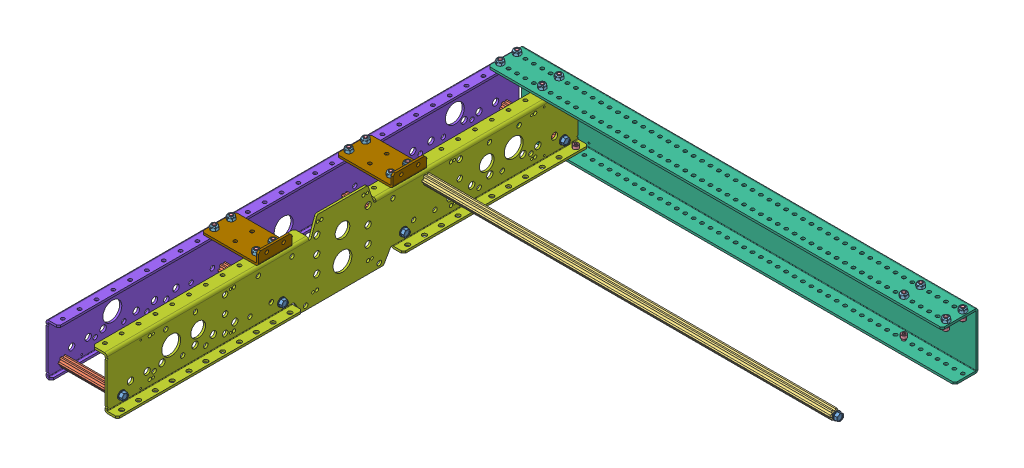
SolidWorks assembly AM14U3 Square Frame Half, configuration Default. Lengths in mm.
Overall size (722.38 116.33 715.14).
56 component instances, 9 part files, 120 mates.
Components (placement in the parent):
- 0.25-20 x 0.75 in Thread Rolling Screw-1: 0.25-20 x 0.75 in Thread Rolling Screw [FHTS 0.25-20-G-0.75-C] at (-600.075 -67.691 639.064) x (-1 0 0) z (0 0.924225 0.381849) size (24.64 12.19 12.19)
- 0.25-20 x 0.75 in Thread Rolling Screw-4: 0.25-20 x 0.75 in Thread Rolling Screw [FHTS 0.25-20-G-0.75-C] at (-600.075 -67.691 -27.94) x (-1 0 0) z (0 0.924225 0.381849) size (24.64 12.19 12.19)
- 0.25-20 x 0.75 in Thread Rolling Screw-5: 0.25-20 x 0.75 in Thread Rolling Screw [FHTS 0.25-20-G-0.75-C] at (-692.15 -67.691 -27.813) size (24.64 12.19 12.19)
- 0.25-20 x 0.75 in Thread Rolling Screw-7: 0.25-20 x 0.75 in Thread Rolling Screw [FHTS 0.25-20-G-0.75-C] at (-603.25 -15.494 178.562) size (24.64 12.19 12.19)
- 0.25-20 x 0.75 in Thread Rolling Screw-9: 0.25-20 x 0.75 in Thread Rolling Screw [FHTS 0.25-20-G-0.75-C] at (-692.15 -67.691 638.937) size (24.64 12.19 12.19)
- 0.25-20 x 0.75 in Thread Rolling Screw-10: 0.25-20 x 0.75 in Thread Rolling Screw [FHTS 0.25-20-G-0.75-C] at (19.05 -15.494 178.562) x (-1 0 0) z (0 0.525103 -0.851039) size (24.64 12.19 12.19)
- 500 Churro 3.375 in-1: 500 Churro 3.375 in [Default] at (-603.25 -67.691 -27.813) x (0 -0.866025 0.5) z (-1 0 0) size (14.66 12.7 85.72)
- 500 Churro 3.375 in-2: 500 Churro 3.375 in [Default] at (-603.25 -67.691 638.937) x (0 -0.866025 0.5) z (-1 0 0) size (14.66 12.7 85.72)
- 500 Churro 24.25 in-1: 500 Churro 24.25 in [Default] at (15.875 -15.494 178.562) x (0 0 -1) z (-1 0 0) size (14.66 12.7 615.95)
- 10-32 x 0.5 in SHCS Screw-19: 10-32 x 0.5 in SHCS Screw [HX-SHCS 0.19-32x1.375x1-C] at (-679.45 -11.43 -11.938) x (0 1 0) z (0 0 1) size (17.53 7.94 7.94)
- 10-32 x 0.5 in SHCS Screw-20: 10-32 x 0.5 in SHCS Screw [HX-SHCS 0.19-32x1.375x1-C] at (-679.45 -11.43 -37.338) x (0 1 0) z (0 0 1) size (17.53 7.94 7.94)
- 10-32 x 0.5 in SHCS Screw-21: 10-32 x 0.5 in SHCS Screw [HX-SHCS 0.19-32x1.375x1-C] at (-615.95 -11.43 -37.338) x (0 1 0) z (0 0 1) size (17.53 7.94 7.94)
- 10-32 x 0.5 in SHCS Screw-22: 10-32 x 0.5 in SHCS Screw [HX-SHCS 0.19-32x1.375x1-C] at (-615.95 -11.43 -11.938) x (0 1 0) z (0 0 1) size (17.53 7.94 7.94)
- 10-32 x 0.5 in SHCS Screw-23: 10-32 x 0.5 in SHCS Screw [HX-SHCS 0.19-32x1.375x1-C] at (-590.55 -73.152 -37.338) x (0 -1 0) z (0 0 1) size (17.53 7.94 7.94)
- 10-32 x 0.5 in SHCS Screw-24: 10-32 x 0.5 in SHCS Screw [HX-SHCS 0.19-32x1.375x1-C] at (-6.35 -11.176 -37.338) x (0 1 0) z (0.222581 0 0.974914) size (17.53 7.94 7.94)
- 10-32 x 0.5 in SHCS Screw-25: 10-32 x 0.5 in SHCS Screw [HX-SHCS 0.19-32x1.375x1-C] at (-6.35 -11.176 -11.938) x (0 1 0) z (0.81526 0 0.579096) size (17.53 7.94 7.94)
- 10-32 x 0.5 in SHCS Screw-26: 10-32 x 0.5 in SHCS Screw [HX-SHCS 0.19-32x1.375x1-C] at (-69.85 -11.176 -37.338) x (0 1 0) z (0 0 1) size (17.53 7.94 7.94)
- 10-32 x 0.5 in SHCS Screw-27: 10-32 x 0.5 in SHCS Screw [HX-SHCS 0.19-32x1.375x1-C] at (-69.85 -11.176 -11.938) x (0 1 0) z (0.111454 0 0.99377) size (17.53 7.94 7.94)
- 10-32 x 0.5 in SHCS Screw-28: 10-32 x 0.5 in SHCS Screw [HX-SHCS 0.19-32x1.375x1-C] at (-95.25 -73.406 -37.338) x (0 -1 0) z (0.007214 0 0.999974) size (17.53 7.94 7.94)
- 10-32 Nylock Nut-19: 10-32 Nylock Nut [Default] at (-679.45 0 -11.938) x (1 0 0) z (0 1 0) size (10.18 11.01 7.1)
- 10-32 Nylock Nut-21: 10-32 Nylock Nut [Default] at (-679.45 0 -37.338) x (1 0 0) z (0 1 0) size (10.18 11.01 7.1)
- 10-32 Nylock Nut-22: 10-32 Nylock Nut [Default] at (-615.95 0 -11.938) x (1 0 0) z (0 1 0) size (10.18 11.01 7.1)
- 10-32 Nylock Nut-23: 10-32 Nylock Nut [Default] at (-615.95 0 -37.338) x (1 0 0) z (0 1 0) size (10.18 11.01 7.1)
- 10-32 Nylock Nut-25: 10-32 Nylock Nut [Default] at (-69.85 0 -11.938) x (1 0 0) z (0 1 0) size (10.18 11.01 7.1)
- 10-32 Nylock Nut-26: 10-32 Nylock Nut [Default] at (-69.85 0 -37.338) x (1 0 0) z (0 1 0) size (10.18 11.01 7.1)
- 10-32 Nylock Nut-27: 10-32 Nylock Nut [Default] at (-6.35 0 -11.938) x (1 0 0) z (0 1 0) size (10.18 11.01 7.1)
- 10-32 Nylock Nut-28: 10-32 Nylock Nut [Default] at (-6.35 0 -37.338) x (1 0 0) z (0 1 0) size (10.18 11.01 7.1)
- 10-32 Nylock Nut-29: 10-32 Nylock Nut [Default] at (-95.25 -84.582 -37.338) x (1 0 0) z (0 -1 0) size (10.18 11.01 7.1)
- 10-32 Nylock Nut-30: 10-32 Nylock Nut [Default] at (-590.55 -84.582 -37.338) x (1 0 0) z (0 -1 0) size (10.18 11.01 7.1)
- 10-32 x 0.5 in SHCS Screw-29: 10-32 x 0.5 in SHCS Screw [HX-SHCS 0.19-32x1.375x1-C] at (-679.45 -11.43 191.262) x (0 1 0) z (0 0 1) size (17.53 7.94 7.94)
- 10-32 x 0.5 in SHCS Screw-30: 10-32 x 0.5 in SHCS Screw [HX-SHCS 0.19-32x1.375x1-C] at (-679.45 -11.43 216.662) x (0 1 0) z (0 0 1) size (17.53 7.94 7.94)
- 10-32 x 0.5 in SHCS Screw-31: 10-32 x 0.5 in SHCS Screw [HX-SHCS 0.19-32x1.375x1-C] at (-615.95 -11.43 191.262) x (0 1 0) z (0 0 1) size (17.53 7.94 7.94)
- 10-32 x 0.5 in SHCS Screw-32: 10-32 x 0.5 in SHCS Screw [HX-SHCS 0.19-32x1.375x1-C] at (-615.95 -11.43 216.662) x (0 1 0) z (0 0 1) size (17.53 7.94 7.94)
- 10-32 x 0.5 in SHCS Screw-33: 10-32 x 0.5 in SHCS Screw [HX-SHCS 0.19-32x1.375x1-C] at (-615.95 -11.43 394.462) x (0 1 0) z (0 0 1) size (17.53 7.94 7.94)
- 10-32 x 0.5 in SHCS Screw-34: 10-32 x 0.5 in SHCS Screw [HX-SHCS 0.19-32x1.375x1-C] at (-615.95 -11.43 419.862) x (0 1 0) z (0 0 1) size (17.53 7.94 7.94)
- 10-32 x 0.5 in SHCS Screw-35: 10-32 x 0.5 in SHCS Screw [HX-SHCS 0.19-32x1.375x1-C] at (-679.45 -11.43 394.462) x (0 1 0) z (0 0 1) size (17.53 7.94 7.94)
- 10-32 x 0.5 in SHCS Screw-36: 10-32 x 0.5 in SHCS Screw [HX-SHCS 0.19-32x1.375x1-C] at (-679.45 -11.43 419.862) x (0 1 0) z (0 0 1) size (17.53 7.94 7.94)
- 10-32 Nylock Nut-31: 10-32 Nylock Nut [Default] at (-679.45 -0.254 419.862) x (1 0 0) z (0 1 0) size (10.18 11.01 7.1)
- 10-32 Nylock Nut-32: 10-32 Nylock Nut [Default] at (-679.45 -0.254 394.462) x (1 0 0) z (0 1 0) size (10.18 11.01 7.1)
- 10-32 Nylock Nut-33: 10-32 Nylock Nut [Default] at (-615.95 -0.254 394.462) x (1 0 0) z (0 1 0) size (10.18 11.01 7.1)
- 10-32 Nylock Nut-34: 10-32 Nylock Nut [Default] at (-615.95 -0.254 419.862) x (1 0 0) z (0 1 0) size (10.18 11.01 7.1)
- 10-32 Nylock Nut-35: 10-32 Nylock Nut [Default] at (-679.45 -0.254 216.662) x (1 0 0) z (0 1 0) size (10.18 11.01 7.1)
- 10-32 Nylock Nut-37: 10-32 Nylock Nut [Default] at (-679.45 -0.254 191.262) x (1 0 0) z (0 1 0) size (10.18 11.01 7.1)
- 10-32 Nylock Nut-38: 10-32 Nylock Nut [Default] at (-615.95 -0.254 216.662) x (1 0 0) z (0 1 0) size (10.18 11.01 7.1)
- 10-32 Nylock Nut-39: 10-32 Nylock Nut [Default] at (-615.95 -0.254 191.262) x (1 0 0) z (0 1 0) size (10.18 11.01 7.1)
- AM14U3 End Plate_Square-1: AM14U3 End Plate_Square [Default] at (-488.098 60.9785 -76.8664) x (1 0 0) z (0 -1 0) size (685.8 53.97 84.58)
- AM14U3 Inner Plate_Square-1: AM14U3 Inner Plate_Square [Default] at (-612.1116 -19.2169 590.6409) x (0 0 -1) z (0 -1 0) size (711.2 38.1 116.33)
- AM14U3 Outer Plate_Square-1: AM14U3 Outer Plate_Square [Default] at (-667.7485 -27.0221 21.6115) x (0 0 1) z (0 -1 0) size (711.2 19.05 77.72)
- Bracket 2x3 Hole Pattern-1: Bracket 2x3 Hole Pattern [Default] at (-685.8 -3.429 445.262) size (85.72 19.05 50.8)
- Bracket 2x3 Hole Pattern-2: Bracket 2x3 Hole Pattern [Default] at (-685.8 -3.429 242.062) size (85.72 19.05 50.8)
- 500 Churro 3.375 in-5: 500 Churro 3.375 in [Default] at (-688.975 -66.929 397.637) x (0 0 -1) z (1 0 0) size (14.66 12.7 85.72)
- 500 Churro 3.375 in-6: 500 Churro 3.375 in [Default] at (-688.975 -66.929 213.487) x (0 0 -1) z (1 0 0) size (14.66 12.7 85.72)
- 0.25-20 x 0.75 in Thread Rolling Screw-11: 0.25-20 x 0.75 in Thread Rolling Screw [FHTS 0.25-20-G-0.75-C] at (-600.075 -66.929 397.637) x (-1 0 0) z (0 0.924225 0.381849) size (24.64 12.19 12.19)
- 0.25-20 x 0.75 in Thread Rolling Screw-12: 0.25-20 x 0.75 in Thread Rolling Screw [FHTS 0.25-20-G-0.75-C] at (-600.075 -66.929 213.487) x (-1 0 0) z (0 0.924225 0.381849) size (24.64 12.19 12.19)
- 0.25-20 x 0.75 in Thread Rolling Screw-13: 0.25-20 x 0.75 in Thread Rolling Screw [FHTS 0.25-20-G-0.75-C] at (-692.15 -66.929 397.637) size (24.64 12.19 12.19)
- 0.25-20 x 0.75 in Thread Rolling Screw-14: 0.25-20 x 0.75 in Thread Rolling Screw [FHTS 0.25-20-G-0.75-C] at (-692.15 -66.929 213.487) size (24.64 12.19 12.19)
Mates (geometry in assembly coordinates):
- Coincident1: coincident aligned: plane of AM14U3 End Plate_Square-1 through (0 0 0) normal (0 1 0); plane of assembly through (0 0 0) normal (0 1 0)
- Coincident2: coincident aligned: plane of AM14U3 End Plate_Square-1 through (0 0 0) normal (0 0 1); plane of assembly through (0 0 0) normal (0 0 1)
- Coincident3: coincident aligned: plane of AM14U3 End Plate_Square-1 through (0 -81.407 -50.8) normal (1 0 0); plane of assembly through (0 0 0) normal (1 0 0)
- Concentric1: concentric anti-aligned: cylinder of AM14U3 End Plate_Square-1 through (-679.45 0 -37.338) axis (0 -1 0) radius 2.667; cylinder of AM14U3 Outer Plate_Square-1 through (-679.45 -81.153 -37.338) axis (0 1 0) radius 2.667
- Concentric2: concentric aligned: cylinder of AM14U3 End Plate_Square-1 through (-679.45 -5.08 -11.938) axis (0 1 0) radius 2.667; cylinder of AM14U3 Outer Plate_Square-1 through (-679.45 -81.153 -11.938) axis (0 1 0) radius 2.667
- Concentric3: concentric anti-aligned: cylinder of AM14U3 End Plate_Square-1 through (-615.95 0 -37.338) axis (0 -1 0) radius 2.667; cylinder of AM14U3 Inner Plate_Square-1 through (-615.95 -81.153 -37.338) axis (0 1 0) radius 2.667
- Coincident5: coincident aligned: circle of AM14U3 End Plate_Square-1; cylinder of AM14U3 Inner Plate_Square-1 through (-615.95 -81.153 -11.938) axis (0 1 0) radius 2.667
- Distance2: distance = 0.254 mm anti-aligned: plane of AM14U3 Inner Plate_Square-1 through (-603.25 -3.429 -100.838) normal (0 1 0); plane of AM14U3 End Plate_Square-1 through (0 -3.175 0) normal (0 -1 0)
- Concentric4: concentric aligned: cylinder of AM14U3 Inner Plate_Square-1 through (-615.95 -81.153 394.462) axis (0 1 0) radius 2.667; cylinder of Bracket 2x3 Hole Pattern-1 through (-615.95 -3.429 394.462) axis (0 1 0) radius 2.667
- Coincident7: coincident aligned: cylinder of AM14U3 Inner Plate_Square-1 through (-615.95 -81.153 419.862) axis (0 1 0) radius 2.667; circle of Bracket 2x3 Hole Pattern-1
- Coincident8: coincident anti-aligned: plane of AM14U3 Inner Plate_Square-1 through (-603.25 -3.429 -100.838) normal (0 1 0); plane of Bracket 2x3 Hole Pattern-1 through (-685.8 -3.429 381.762) normal (0 -1 0)
- Concentric5: concentric aligned: cylinder of AM14U3 Inner Plate_Square-1 through (-615.95 -81.153 216.662) axis (0 1 0) radius 2.667; cylinder of Bracket 2x3 Hole Pattern-2 through (-615.95 -3.429 216.662) axis (0 1 0) radius 2.667
- Concentric6: concentric aligned: cylinder of AM14U3 Inner Plate_Square-1 through (-615.95 -81.153 191.262) axis (0 1 0) radius 2.667; cylinder of Bracket 2x3 Hole Pattern-2 through (-615.95 -3.429 191.262) axis (0 1 0) radius 2.667
- Coincident9: coincident anti-aligned: plane of AM14U3 Inner Plate_Square-1 through (-603.25 -3.429 -100.838) normal (0 1 0); plane of Bracket 2x3 Hole Pattern-2 through (-685.8 -3.429 178.562) normal (0 -1 0)
- Concentric25: concentric anti-aligned: cylinder of AM14U3 Outer Plate_Square-1 through (-673.1 -67.691 -27.813) axis (-1 0 0) radius 3.3528; cylinder of 500 Churro 3.375 in-1 through (-688.975 -67.691 -27.813) axis (1 0 0) radius 2.9337
- Concentric26: concentric anti-aligned: cylinder of AM14U3 Outer Plate_Square-1 through (-673.1 -67.691 638.937) axis (-1 0 0) radius 3.3528; cylinder of 500 Churro 3.375 in-2 through (-688.975 -67.691 638.937) axis (1 0 0) radius 2.9337
- Coincident28: coincident anti-aligned: plane of AM14U3 Outer Plate_Square-1 through (-688.975 -7.366 -100.838) normal (1 0 0); plane of 500 Churro 3.375 in-2 through (-688.975 -70.866 644.4363) normal (-1 0 0)
- Parallel1: parallel aligned: plane of AM14U3 Outer Plate_Square-1 through (-688.975 -81.153 711.962) normal (0 -1 0); plane of 500 Churro 3.375 in-2 through (-688.975 -74.041 635.2708) normal (0 -1 0)
- Coincident30: coincident anti-aligned: plane of AM14U3 Outer Plate_Square-1 through (-688.975 -7.366 -100.838) normal (1 0 0); plane of 500 Churro 3.375 in-1 through (-688.975 -70.866 -22.3137) normal (-1 0 0)
- Parallel2: parallel aligned: plane of AM14U3 Outer Plate_Square-1 through (-688.975 -81.153 711.962) normal (0 -1 0); plane of 500 Churro 3.375 in-1 through (-688.975 -74.041 -31.4792) normal (0 -1 0)
- Distance3: distance = 0.254 mm anti-aligned: plane of AM14U3 Outer Plate_Square-1 through (-688.975 -3.429 711.962) normal (0 1 0); plane of AM14U3 End Plate_Square-1 through (0 -3.175 0) normal (0 -1 0)
- Concentric29: concentric anti-aligned: circle of AM14U3 Inner Plate_Square-1; cylinder of 500 Churro 24.25 in-1 through (-600.075 -15.494 178.562) axis (1 0 0) radius 2.9337
- Coincident37: coincident anti-aligned: plane of AM14U3 Inner Plate_Square-1 through (-600.075 -7.366 711.962) normal (1 0 0); plane of 500 Churro 24.25 in-1 through (-600.075 -18.669 173.0627) normal (-1 0 0)
- Concentric301: concentric aligned: cylinder of AM14U3 Inner Plate_Square-1 through (-622.3 -67.691 639.064) axis (1 0 0) radius 3.3528; cylinder of 0.25-20 x 0.75 in Thread Rolling Screw-1 through (-600.075 -67.691 639.064) axis (1 0 0) radius 3.175
- Coincident381: coincident anti-aligned: plane of AM14U3 Inner Plate_Square-1 through (-600.075 -7.366 711.962) normal (1 0 0); plane of 0.25-20 x 0.75 in Thread Rolling Screw-1 through (-600.075 -68.9034 641.9984) normal (-1 0 0)
- Concentric331: concentric aligned: cylinder of AM14U3 Inner Plate_Square-1 through (-622.3 -67.691 -27.94) axis (1 0 0) radius 3.3528; cylinder of 0.25-20 x 0.75 in Thread Rolling Screw-4 through (-600.075 -67.691 -27.94) axis (1 0 0) radius 3.175
- Coincident411: coincident anti-aligned: plane of AM14U3 Inner Plate_Square-1 through (-600.075 -7.366 711.962) normal (1 0 0); plane of 0.25-20 x 0.75 in Thread Rolling Screw-4 through (-600.075 -68.9034 -25.0056) normal (-1 0 0)
- Concentric341: concentric aligned: cylinder of AM14U3 Outer Plate_Square-1 through (-673.1 -67.691 -27.813) axis (-1 0 0) radius 3.3528; cylinder of 0.25-20 x 0.75 in Thread Rolling Screw-5 through (-692.15 -67.691 -27.813) axis (-1 0 0) radius 3.175
- Coincident421: coincident anti-aligned: plane of AM14U3 Outer Plate_Square-1 through (-692.15 -7.366 -100.838) normal (-1 0 0); plane of 0.25-20 x 0.75 in Thread Rolling Screw-5 through (-692.15 -64.516 -27.813) normal (1 0 0)
- Concentric361: concentric aligned: cylinder of AM14U3 Inner Plate_Square-1 through (-584.2 -15.494 178.562) axis (-1 0 0) radius 3.3528; cylinder of 0.25-20 x 0.75 in Thread Rolling Screw-7 through (-603.25 -15.494 178.562) axis (-1 0 0) radius 3.175
- Coincident441: coincident anti-aligned: plane of AM14U3 Inner Plate_Square-1 through (-603.25 -7.366 711.962) normal (-1 0 0); plane of 0.25-20 x 0.75 in Thread Rolling Screw-7 through (-603.25 -12.319 178.562) normal (1 0 0)
- Concentric381: concentric aligned: cylinder of AM14U3 Outer Plate_Square-1 through (-673.1 -67.691 638.937) axis (-1 0 0) radius 3.3528; cylinder of 0.25-20 x 0.75 in Thread Rolling Screw-9 through (-692.15 -67.691 638.937) axis (-1 0 0) radius 3.175
- Coincident461: coincident anti-aligned: plane of AM14U3 Outer Plate_Square-1 through (-692.15 -7.366 -100.838) normal (-1 0 0); plane of 0.25-20 x 0.75 in Thread Rolling Screw-9 through (-692.15 -64.516 638.937) normal (1 0 0)
- Concentric39: concentric aligned: cylinder of 500 Churro 24.25 in-1 through (-600.075 -15.494 178.562) axis (1 0 0) radius 2.9337; cylinder of 0.25-20 x 0.75 in Thread Rolling Screw-10 through (19.05 -15.494 178.562) axis (1 0 0) radius 3.175
- Distance4: distance = 3.175 mm anti-aligned: plane of 500 Churro 24.25 in-1 through (15.875 -18.669 173.0627) normal (1 0 0); plane of 0.25-20 x 0.75 in Thread Rolling Screw-10 through (19.05 -12.792 180.2292) normal (-1 0 0)
- Parallel5: parallel aligned: plane of AM14U3 Inner Plate_Square-1 through (-603.25 -3.429 -100.838) normal (0 1 0); plane of 500 Churro 24.25 in-1 through (-600.075 -9.144 176.9745) normal (0 1 0)
- Concentric4721: concentric anti-aligned: cylinder of AM14U3 Outer Plate_Square-1 through (-679.45 -81.153 -11.938) axis (0 1 0) radius 2.667; cylinder of 10-32 x 0.5 in SHCS Screw-19 through (-679.45 -43.18 -11.938) axis (0 -1 0) radius 3.9688
- Coincident5621: coincident anti-aligned: plane of AM14U3 Outer Plate_Square-1 through (-688.975 -6.604 711.962) normal (0 -1 0); plane of 10-32 x 0.5 in SHCS Screw-19 through (-683.4187 -6.604 -11.938) normal (0 1 0)
- Concentric4731: concentric anti-aligned: cylinder of AM14U3 Outer Plate_Square-1 through (-679.45 -81.153 -37.338) axis (0 1 0) radius 2.667; cylinder of 10-32 x 0.5 in SHCS Screw-20 through (-679.45 -43.18 -37.338) axis (0 -1 0) radius 3.9688
- Coincident5631: coincident anti-aligned: plane of AM14U3 Outer Plate_Square-1 through (-688.975 -6.604 711.962) normal (0 -1 0); plane of 10-32 x 0.5 in SHCS Screw-20 through (-683.4187 -6.604 -37.338) normal (0 1 0)
- Concentric4741: concentric anti-aligned: cylinder of AM14U3 Inner Plate_Square-1 through (-615.95 -81.153 -37.338) axis (0 1 0) radius 2.667; cylinder of 10-32 x 0.5 in SHCS Screw-21 through (-615.95 -43.18 -37.338) axis (0 -1 0) radius 3.9688
- Coincident5641: coincident anti-aligned: plane of AM14U3 Inner Plate_Square-1 through (-603.25 -6.604 -100.838) normal (0 -1 0); plane of 10-32 x 0.5 in SHCS Screw-21 through (-619.9187 -6.604 -37.338) normal (0 1 0)
- Concentric4751: concentric anti-aligned: cylinder of AM14U3 Inner Plate_Square-1 through (-615.95 -81.153 -11.938) axis (0 1 0) radius 2.667; cylinder of 10-32 x 0.5 in SHCS Screw-22 through (-615.95 -43.18 -11.938) axis (0 -1 0) radius 3.9688
- Coincident5651: coincident anti-aligned: plane of AM14U3 Inner Plate_Square-1 through (-603.25 -6.604 -100.838) normal (0 -1 0); plane of 10-32 x 0.5 in SHCS Screw-22 through (-619.9187 -6.604 -11.938) normal (0 1 0)
- Concentric4761: concentric aligned: cylinder of AM14U3 Inner Plate_Square-1 through (-590.55 -81.153 -37.338) axis (0 1 0) radius 3.3528; cylinder of 10-32 x 0.5 in SHCS Screw-23 through (-590.55 -41.402 -37.338) axis (0 1 0) radius 3.9688
- Coincident5661: coincident anti-aligned: plane of AM14U3 Inner Plate_Square-1 through (-600.075 -77.978 -100.838) normal (0 1 0); plane of 10-32 x 0.5 in SHCS Screw-23 through (-586.5813 -77.978 -37.338) normal (0 -1 0)
- Concentric478: concentric aligned: cylinder of AM14U3 End Plate_Square-1 through (-6.35 0 -37.338) axis (0 -1 0) radius 2.667; cylinder of 10-32 x 0.5 in SHCS Screw-24 through (-6.35 -42.926 -37.338) axis (0 -1 0) radius 2.413
- Concentric479: concentric anti-aligned: cylinder of AM14U3 End Plate_Square-1 through (-6.35 -5.08 -11.938) axis (0 1 0) radius 2.667; cylinder of 10-32 x 0.5 in SHCS Screw-25 through (-6.35 -42.926 -11.938) axis (0 -1 0) radius 2.413
- Coincident567: coincident aligned: plane of 10-32 x 0.5 in SHCS Screw-24 through (-10.2192 -6.35 -36.4546) normal (0 1 0); plane of 10-32 x 0.5 in SHCS Screw-25 through (-8.6483 -6.35 -8.7024) normal (0 1 0)
- Concentric480: concentric aligned: cylinder of AM14U3 End Plate_Square-1 through (-69.85 0 -37.338) axis (0 -1 0) radius 2.667; cylinder of 10-32 x 0.5 in SHCS Screw-26 through (-69.85 -42.926 -37.338) axis (0 -1 0) radius 2.413
- Concentric481: concentric anti-aligned: cylinder of AM14U3 End Plate_Square-1 through (-69.85 -5.08 -11.938) axis (0 1 0) radius 2.667; cylinder of 10-32 x 0.5 in SHCS Screw-27 through (-69.85 -42.926 -11.938) axis (0 -1 0) radius 2.413
- Coincident568: coincident aligned: plane of 10-32 x 0.5 in SHCS Screw-26 through (-73.8188 -6.35 -37.338) normal (0 1 0); plane of 10-32 x 0.5 in SHCS Screw-27 through (-73.794 -6.35 -11.4957) normal (0 1 0)
- Coincident569: coincident aligned: plane of 10-32 x 0.5 in SHCS Screw-25 through (-8.6483 -6.35 -8.7024) normal (0 1 0); plane of 10-32 x 0.5 in SHCS Screw-27 through (-73.794 -6.35 -11.4957) normal (0 1 0)
- Distance5: distance = 3.175 mm anti-aligned: plane of AM14U3 End Plate_Square-1 through (0 -3.175 0) normal (0 -1 0); plane of 10-32 x 0.5 in SHCS Screw-27 through (-73.794 -6.35 -11.4957) normal (0 1 0)
- Concentric482: concentric aligned: circle of AM14U3 End Plate_Square-1; cylinder of 10-32 x 0.5 in SHCS Screw-28 through (-95.25 -41.656 -37.338) axis (0 1 0) radius 2.413
- Distance6: distance = 3.175 mm anti-aligned: plane of AM14U3 End Plate_Square-1 through (-787.4 -81.407 -19.05) normal (0 1 0); plane of 10-32 x 0.5 in SHCS Screw-28 through (-91.2814 -78.232 -37.3666) normal (0 -1 0)
- Concentric4831: concentric aligned: cylinder of AM14U3 End Plate_Square-1 through (-679.45 -5.08 -11.938) axis (0 1 0) radius 2.667; cylinder of 10-32 Nylock Nut-19 through (-679.45 5.9531 -11.938) axis (0 1 0) radius 2.0193
- Coincident5721: coincident anti-aligned: plane of AM14U3 End Plate_Square-1 through (0 0 0) normal (0 1 0); plane of 10-32 Nylock Nut-19 through (-679.45 0 -11.938) normal (0 -1 0)
- Concentric4841: concentric anti-aligned: cylinder of AM14U3 End Plate_Square-1 through (-679.45 0 -37.338) axis (0 -1 0) radius 2.667; cylinder of 10-32 Nylock Nut-21 through (-679.45 5.9531 -37.338) axis (0 1 0) radius 2.0193
- Coincident5731: coincident anti-aligned: plane of AM14U3 End Plate_Square-1 through (0 0 0) normal (0 1 0); plane of 10-32 Nylock Nut-21 through (-679.45 0 -37.338) normal (0 -1 0)
- Concentric4851: concentric aligned: cylinder of AM14U3 End Plate_Square-1 through (-615.95 -5.08 -11.938) axis (0 1 0) radius 2.667; cylinder of 10-32 Nylock Nut-22 through (-615.95 5.9531 -11.938) axis (0 1 0) radius 2.0193
- Coincident5741: coincident anti-aligned: plane of AM14U3 End Plate_Square-1 through (0 0 0) normal (0 1 0); plane of 10-32 Nylock Nut-22 through (-615.95 0 -11.938) normal (0 -1 0)
- Concentric4861: concentric anti-aligned: cylinder of AM14U3 End Plate_Square-1 through (-615.95 0 -37.338) axis (0 -1 0) radius 2.667; cylinder of 10-32 Nylock Nut-23 through (-615.95 5.9531 -37.338) axis (0 1 0) radius 2.0193
- Coincident5751: coincident anti-aligned: plane of AM14U3 End Plate_Square-1 through (0 0 0) normal (0 1 0); plane of 10-32 Nylock Nut-23 through (-615.95 0 -37.338) normal (0 -1 0)
- Concentric4871: concentric aligned: cylinder of AM14U3 End Plate_Square-1 through (-69.85 -5.08 -11.938) axis (0 1 0) radius 2.667; cylinder of 10-32 Nylock Nut-25 through (-69.85 5.9531 -11.938) axis (0 1 0) radius 2.0193
- Coincident5771: coincident anti-aligned: plane of AM14U3 End Plate_Square-1 through (0 0 0) normal (0 1 0); plane of 10-32 Nylock Nut-25 through (-69.85 0 -11.938) normal (0 -1 0)
- Concentric4881: concentric anti-aligned: cylinder of AM14U3 End Plate_Square-1 through (-69.85 0 -37.338) axis (0 -1 0) radius 2.667; cylinder of 10-32 Nylock Nut-26 through (-69.85 5.9531 -37.338) axis (0 1 0) radius 2.0193
- Coincident5781: coincident anti-aligned: plane of AM14U3 End Plate_Square-1 through (0 0 0) normal (0 1 0); plane of 10-32 Nylock Nut-26 through (-69.85 0 -37.338) normal (0 -1 0)
- Concentric4891: concentric aligned: cylinder of AM14U3 End Plate_Square-1 through (-6.35 -5.08 -11.938) axis (0 1 0) radius 2.667; cylinder of 10-32 Nylock Nut-27 through (-6.35 5.9531 -11.938) axis (0 1 0) radius 2.0193
- Coincident5791: coincident anti-aligned: plane of AM14U3 End Plate_Square-1 through (0 0 0) normal (0 1 0); plane of 10-32 Nylock Nut-27 through (-6.35 0 -11.938) normal (0 -1 0)
- Concentric4901: concentric anti-aligned: cylinder of AM14U3 End Plate_Square-1 through (-6.35 0 -37.338) axis (0 -1 0) radius 2.667; cylinder of 10-32 Nylock Nut-28 through (-6.35 5.9531 -37.338) axis (0 1 0) radius 2.0193
- Coincident5801: coincident anti-aligned: plane of AM14U3 End Plate_Square-1 through (0 0 0) normal (0 1 0); plane of 10-32 Nylock Nut-28 through (-6.35 0 -37.338) normal (0 -1 0)
- Concentric4911: concentric aligned: cylinder of AM14U3 End Plate_Square-1 through (-95.25 0 -37.338) axis (0 -1 0) radius 2.667; cylinder of 10-32 Nylock Nut-29 through (-95.25 -90.5351 -37.338) axis (0 -1 0) radius 2.0193
- Coincident5811: coincident anti-aligned: plane of AM14U3 End Plate_Square-1 through (-787.4 -84.582 -19.05) normal (0 -1 0); plane of 10-32 Nylock Nut-29 through (-95.25 -84.582 -37.338) normal (0 1 0)
- Concentric4921: concentric aligned: cylinder of AM14U3 End Plate_Square-1 through (-590.55 0 -37.338) axis (0 -1 0) radius 2.667; cylinder of 10-32 Nylock Nut-30 through (-590.55 -90.5351 -37.338) axis (0 -1 0) radius 2.0193
- Coincident5821: coincident anti-aligned: plane of AM14U3 End Plate_Square-1 through (-787.4 -84.582 -19.05) normal (0 -1 0); plane of 10-32 Nylock Nut-30 through (-590.55 -84.582 -37.338) normal (0 1 0)
- Concentric4931: concentric anti-aligned: cylinder of AM14U3 Outer Plate_Square-1 through (-679.45 -81.153 191.262) axis (0 1 0) radius 2.667; cylinder of 10-32 x 0.5 in SHCS Screw-29 through (-679.45 -43.18 191.262) axis (0 -1 0) radius 3.9688
- Coincident5831: coincident anti-aligned: plane of AM14U3 Outer Plate_Square-1 through (-688.975 -6.604 711.962) normal (0 -1 0); plane of 10-32 x 0.5 in SHCS Screw-29 through (-683.4187 -6.604 191.262) normal (0 1 0)
- Concentric4941: concentric anti-aligned: cylinder of AM14U3 Outer Plate_Square-1 through (-679.45 -81.153 216.662) axis (0 1 0) radius 2.667; cylinder of 10-32 x 0.5 in SHCS Screw-30 through (-679.45 -43.18 216.662) axis (0 -1 0) radius 3.9688
- Coincident5841: coincident anti-aligned: plane of AM14U3 Outer Plate_Square-1 through (-688.975 -6.604 711.962) normal (0 -1 0); plane of 10-32 x 0.5 in SHCS Screw-30 through (-683.4187 -6.604 216.662) normal (0 1 0)
- Concentric4951: concentric anti-aligned: cylinder of AM14U3 Inner Plate_Square-1 through (-615.95 -81.153 191.262) axis (0 1 0) radius 2.667; cylinder of 10-32 x 0.5 in SHCS Screw-31 through (-615.95 -43.18 191.262) axis (0 -1 0) radius 3.9688
- Coincident5851: coincident anti-aligned: plane of AM14U3 Inner Plate_Square-1 through (-603.25 -6.604 -100.838) normal (0 -1 0); plane of 10-32 x 0.5 in SHCS Screw-31 through (-619.9187 -6.604 191.262) normal (0 1 0)
- Concentric4961: concentric anti-aligned: cylinder of AM14U3 Inner Plate_Square-1 through (-615.95 -81.153 216.662) axis (0 1 0) radius 2.667; cylinder of 10-32 x 0.5 in SHCS Screw-32 through (-615.95 -43.18 216.662) axis (0 -1 0) radius 3.9688
- Coincident5861: coincident anti-aligned: plane of AM14U3 Inner Plate_Square-1 through (-603.25 -6.604 -100.838) normal (0 -1 0); plane of 10-32 x 0.5 in SHCS Screw-32 through (-619.9187 -6.604 216.662) normal (0 1 0)
- Concentric4971: concentric anti-aligned: cylinder of AM14U3 Inner Plate_Square-1 through (-615.95 -81.153 394.462) axis (0 1 0) radius 2.667; cylinder of 10-32 x 0.5 in SHCS Screw-33 through (-615.95 -43.18 394.462) axis (0 -1 0) radius 3.9688
- Coincident5871: coincident anti-aligned: plane of AM14U3 Inner Plate_Square-1 through (-603.25 -6.604 -100.838) normal (0 -1 0); plane of 10-32 x 0.5 in SHCS Screw-33 through (-619.9187 -6.604 394.462) normal (0 1 0)
- Concentric4981: concentric anti-aligned: cylinder of AM14U3 Inner Plate_Square-1 through (-615.95 -81.153 419.862) axis (0 1 0) radius 2.667; cylinder of 10-32 x 0.5 in SHCS Screw-34 through (-615.95 -43.18 419.862) axis (0 -1 0) radius 3.9688
- Coincident5881: coincident anti-aligned: plane of AM14U3 Inner Plate_Square-1 through (-603.25 -6.604 -100.838) normal (0 -1 0); plane of 10-32 x 0.5 in SHCS Screw-34 through (-619.9187 -6.604 419.862) normal (0 1 0)
- Concentric4991: concentric anti-aligned: cylinder of AM14U3 Outer Plate_Square-1 through (-679.45 -81.153 394.462) axis (0 1 0) radius 2.667; cylinder of 10-32 x 0.5 in SHCS Screw-35 through (-679.45 -43.18 394.462) axis (0 -1 0) radius 3.9688
- Coincident5891: coincident anti-aligned: plane of AM14U3 Outer Plate_Square-1 through (-688.975 -6.604 711.962) normal (0 -1 0); plane of 10-32 x 0.5 in SHCS Screw-35 through (-683.4187 -6.604 394.462) normal (0 1 0)
- Concentric5001: concentric anti-aligned: cylinder of AM14U3 Outer Plate_Square-1 through (-679.45 -81.153 419.862) axis (0 1 0) radius 2.667; cylinder of 10-32 x 0.5 in SHCS Screw-36 through (-679.45 -43.18 419.862) axis (0 -1 0) radius 3.9688
- Coincident5901: coincident anti-aligned: plane of AM14U3 Outer Plate_Square-1 through (-688.975 -6.604 711.962) normal (0 -1 0); plane of 10-32 x 0.5 in SHCS Screw-36 through (-683.4187 -6.604 419.862) normal (0 1 0)
- Concentric5011: concentric aligned: cylinder of Bracket 2x3 Hole Pattern-1 through (-679.45 -3.429 419.862) axis (0 1 0) radius 2.667; cylinder of 10-32 Nylock Nut-31 through (-679.45 5.6991 419.862) axis (0 1 0) radius 2.0193
- Coincident5911: coincident anti-aligned: plane of Bracket 2x3 Hole Pattern-1 through (-685.8 -0.254 381.762) normal (0 1 0); plane of 10-32 Nylock Nut-31 through (-679.45 -0.254 419.862) normal (0 -1 0)
- Concentric5021: concentric aligned: cylinder of Bracket 2x3 Hole Pattern-1 through (-679.45 -3.429 394.462) axis (0 1 0) radius 2.667; cylinder of 10-32 Nylock Nut-32 through (-679.45 5.6991 394.462) axis (0 1 0) radius 2.0193
- Coincident5921: coincident anti-aligned: plane of Bracket 2x3 Hole Pattern-1 through (-685.8 -0.254 381.762) normal (0 1 0); plane of 10-32 Nylock Nut-32 through (-679.45 -0.254 394.462) normal (0 -1 0)
- Concentric5031: concentric aligned: cylinder of Bracket 2x3 Hole Pattern-1 through (-615.95 -3.429 394.462) axis (0 1 0) radius 2.667; cylinder of 10-32 Nylock Nut-33 through (-615.95 5.6991 394.462) axis (0 1 0) radius 2.0193
- Coincident5931: coincident anti-aligned: plane of Bracket 2x3 Hole Pattern-1 through (-685.8 -0.254 381.762) normal (0 1 0); plane of 10-32 Nylock Nut-33 through (-615.95 -0.254 394.462) normal (0 -1 0)
- Concentric5041: concentric aligned: cylinder of Bracket 2x3 Hole Pattern-1 through (-615.95 -3.429 419.862) axis (0 1 0) radius 2.667; cylinder of 10-32 Nylock Nut-34 through (-615.95 5.6991 419.862) axis (0 1 0) radius 2.0193
- Coincident5941: coincident anti-aligned: plane of Bracket 2x3 Hole Pattern-1 through (-685.8 -0.254 381.762) normal (0 1 0); plane of 10-32 Nylock Nut-34 through (-615.95 -0.254 419.862) normal (0 -1 0)
- Concentric5051: concentric aligned: cylinder of Bracket 2x3 Hole Pattern-2 through (-679.45 -3.429 216.662) axis (0 1 0) radius 2.667; cylinder of 10-32 Nylock Nut-35 through (-679.45 5.6991 216.662) axis (0 1 0) radius 2.0193
- Coincident5951: coincident anti-aligned: plane of Bracket 2x3 Hole Pattern-2 through (-685.8 -0.254 178.562) normal (0 1 0); plane of 10-32 Nylock Nut-35 through (-679.45 -0.254 216.662) normal (0 -1 0)
- Concentric5061: concentric aligned: cylinder of Bracket 2x3 Hole Pattern-2 through (-679.45 -3.429 191.262) axis (0 1 0) radius 2.667; cylinder of 10-32 Nylock Nut-37 through (-679.45 5.6991 191.262) axis (0 1 0) radius 2.0193
- Coincident5961: coincident anti-aligned: plane of Bracket 2x3 Hole Pattern-2 through (-685.8 -0.254 178.562) normal (0 1 0); plane of 10-32 Nylock Nut-37 through (-679.45 -0.254 191.262) normal (0 -1 0)
- Concentric5071: concentric aligned: cylinder of Bracket 2x3 Hole Pattern-2 through (-615.95 -3.429 216.662) axis (0 1 0) radius 2.667; cylinder of 10-32 Nylock Nut-38 through (-615.95 5.6991 216.662) axis (0 1 0) radius 2.0193
- Coincident5971: coincident anti-aligned: plane of Bracket 2x3 Hole Pattern-2 through (-685.8 -0.254 178.562) normal (0 1 0); plane of 10-32 Nylock Nut-38 through (-615.95 -0.254 216.662) normal (0 -1 0)
- Concentric5081: concentric aligned: cylinder of Bracket 2x3 Hole Pattern-2 through (-615.95 -3.429 191.262) axis (0 1 0) radius 2.667; cylinder of 10-32 Nylock Nut-39 through (-615.95 5.6991 191.262) axis (0 1 0) radius 2.0193
- Coincident5981: coincident anti-aligned: plane of Bracket 2x3 Hole Pattern-2 through (-685.8 -0.254 178.562) normal (0 1 0); plane of 10-32 Nylock Nut-39 through (-615.95 -0.254 191.262) normal (0 -1 0)
- Concentric5082: concentric anti-aligned: circle of AM14U3 Inner Plate_Square-1; cylinder of 500 Churro 3.375 in-5 through (-603.25 -66.929 397.637) axis (-1 0 0) radius 2.9337
- Concentric5083: concentric anti-aligned: cylinder of AM14U3 Inner Plate_Square-1 through (-622.3 -66.929 213.487) axis (1 0 0) radius 3.3528; cylinder of 500 Churro 3.375 in-6 through (-603.25 -66.929 213.487) axis (-1 0 0) radius 2.9337
- Coincident5982: coincident aligned: plane of 500 Churro 3.375 in-5 through (-603.25 -63.754 392.1377) normal (1 0 0); plane of 500 Churro 3.375 in-6 through (-603.25 -63.754 207.9877) normal (1 0 0)
- Coincident5983: coincident anti-aligned: plane of AM14U3 Inner Plate_Square-1 through (-603.25 -7.366 711.962) normal (-1 0 0); plane of 500 Churro 3.375 in-5 through (-603.25 -63.754 392.1377) normal (1 0 0)
- Concentric50841: concentric aligned: cylinder of AM14U3 Inner Plate_Square-1 through (-622.3 -66.929 397.637) axis (1 0 0) radius 3.3528; cylinder of 0.25-20 x 0.75 in Thread Rolling Screw-11 through (-600.075 -66.929 397.637) axis (1 0 0) radius 3.175
- Coincident59841: coincident anti-aligned: plane of AM14U3 Inner Plate_Square-1 through (-600.075 -7.366 711.962) normal (1 0 0); plane of 0.25-20 x 0.75 in Thread Rolling Screw-11 through (-600.075 -68.1414 400.5714) normal (-1 0 0)
- Concentric50851: concentric aligned: cylinder of AM14U3 Inner Plate_Square-1 through (-622.3 -66.929 213.487) axis (1 0 0) radius 3.3528; cylinder of 0.25-20 x 0.75 in Thread Rolling Screw-12 through (-600.075 -66.929 213.487) axis (1 0 0) radius 3.175
- Coincident59851: coincident anti-aligned: plane of AM14U3 Inner Plate_Square-1 through (-600.075 -7.366 711.962) normal (1 0 0); plane of 0.25-20 x 0.75 in Thread Rolling Screw-12 through (-600.075 -68.1414 216.4214) normal (-1 0 0)
- Concentric50861: concentric aligned: cylinder of AM14U3 Outer Plate_Square-1 through (-673.1 -66.929 397.637) axis (-1 0 0) radius 3.3782; cylinder of 0.25-20 x 0.75 in Thread Rolling Screw-13 through (-692.15 -66.929 397.637) axis (-1 0 0) radius 3.175
- Coincident59861: coincident anti-aligned: plane of AM14U3 Outer Plate_Square-1 through (-692.15 -7.366 -100.838) normal (-1 0 0); plane of 0.25-20 x 0.75 in Thread Rolling Screw-13 through (-692.15 -63.754 397.637) normal (1 0 0)
- Concentric50871: concentric aligned: cylinder of AM14U3 Outer Plate_Square-1 through (-673.1 -66.929 213.487) axis (-1 0 0) radius 3.3782; cylinder of 0.25-20 x 0.75 in Thread Rolling Screw-14 through (-692.15 -66.929 213.487) axis (-1 0 0) radius 3.175
- Coincident59871: coincident anti-aligned: plane of AM14U3 Outer Plate_Square-1 through (-692.15 -7.366 -100.838) normal (-1 0 0); plane of 0.25-20 x 0.75 in Thread Rolling Screw-14 through (-692.15 -63.754 213.487) normal (1 0 0)
